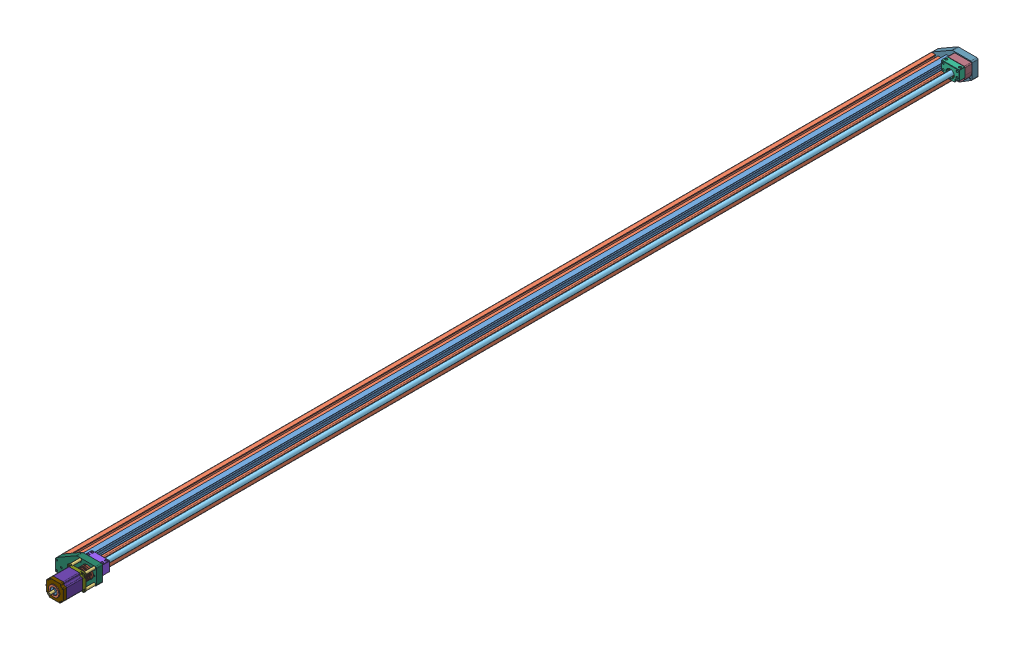
SolidWorks assembly Y Assembly, configuration Default. Lengths in mm.
Overall size (158.33 106.76 3065.8).
33 component instances, 22 part files, 30 mates.
Components (placement in the parent):
- Y 2897 track-1: Y 2897 track [Default] at (-10.0871 17.7743 0) x (-1 0 0) z (0 0 -1) size (23.2 18 2897)
- Y 2897 40x80 Aluminiun Extrusion-1: Y 2897 40x80 Aluminiun Extrusion [Default] at (-31.0945 -20 -2897) x (0 -1 0) z (0 0 -1) size (40 80 2897)
- Y Motor Spacer-1: Y Motor Spacer [Default] at (0 0 20) size (8.2 8.2 33.3)
- Y Screw-3: Y Screw [Default] at (30.9419 11.3979 -2874) x (-0.661218 -0.750194 0) z (0.750194 -0.661218 0) size (71.93 2929.31 73.44)
  - circlip for shafts normal_din2-1: circlip for shafts normal_din2 [Circlip DIN 471 - 10 x 1] at (-3.7337 -2.85 3.3256) x (-0.006153 0 0.999981) z (0 -1 0) size (12.16 14.7 1)
  - Y 2900 Ball Screw SFU1605-1: Y 2900 Ball Screw SFU1605 [По умолчанию] at (-2.5053 -2813.0019 -2.488) x (0 -1 0) z (-0.978395 0 -0.206744) size (2900 19.01 16.42)
  - BF12 BALLSCREW END SUPPORT-1: BF12 BALLSCREW END SUPPORT [Default] at (1.6957 -8.2224 -8.9513) x (0.661218 0 -0.750194) z (0 -1 0) size (60 43 20)
    - BF12-1-1: BF12-1 [Default] at (-12.8001 22.0446 -8.2224) size (60 43 20)
    - 6000-Bearing-1: 6000-Bearing [Default] at (-12.8001 4.0446 -2.2224) size (26 26 8)
  - BK12 BALLSCREW END SUPPORT-1: BK12 BALLSCREW END SUPPORT [Default] at (-17.1749 -2862.0215 6.1787) x (-0.661218 0 0.750194) z (0 1 0) size (60 43 25)
    - BK12-1-1: BK12-1 [Default] at (-11.028 26.197 -11.9785) size (60 43 25)
    - BK12-2-5: BK12-2 [Default] at (-11.028 8.197 8.0215) size (24 24 3)
    - 6001-Bearing-3: 6001-Bearing [Default] at (-11.028 8.197 0.0215) size (28 28 8)
    - 6001-Bearing-4: 6001-Bearing [Default] at (-11.028 8.197 -7.9785) size (28 28 8)
    - BK12-2-6: BK12-2 [Default] at (-11.028 8.197 -7.9785) x (-1 0 0) z (0 0 -1) size (24 24 3)
  - Flexible Coupling MKS-C-2-C-150-08-10-1: Flexible Coupling MKS-C-2-C-150-08-10 [Default] at (0.9582 -2912.8649 12.5563) x (-0.304543 0 0.952499) z (0.952499 0 0.304543) size (38.1 41.32 38.1)
    - MKS-C-2-C-150-08-10-1-1: MKS-C-2-C-150-08-10-1 [Default] at (-7.3634 16.4351 -7.2802) size (38.1 41.32 38.1)
    - socket head cap screw_am2-3: socket head cap screw_am2 [B18.3.1M - 4 x 0.7 x 20 Hex SHCS -- 20NHX] at (3.6866 10.4351 -20.2802) x (-1 0 0) z (0 0.924225 0.381849) size (24 7 7)
    - socket head cap screw_am2-4: socket head cap screw_am2 [B18.3.1M - 4 x 0.7 x 20 Hex SHCS -- 20NHX] at (-20.3634 -18.8649 -18.3302) x (0 0 1) z (-1 0 0) size (24 7 7)
- Y Screw end Support Spacer-1: Y Screw end Support Spacer [Default] at (44.8111 84 -2897) x (-1 0 0) z (0 0 1) size (60 55 23)
- Y Screw Support motor top end-1: Y Screw Support motor top end [Default] at (-541.0945 -130 -2917) x (0 -1 0) z (0 0 1) size (80.2 137 20)
- Y Screw Support motor top-1: Y Screw Support motor top [Default] at (-541.0945 -130 0) x (0 -1 0) z (0 0 1) size (80.2 137 20)
- Nema 23 Stepper Motor 57BYGH311D-12-1: Nema 23 Stepper Motor 57BYGH311D-12 [Default] at (24.3309 -0.4138 61.9741) x (-1 0 0) z (0 0 -1) size (58.4 56.4 121)
  - 57BYGH311D-12-1-1: 57BYGH311D-12-1 [Default] at (-11.5747 12.4138 -2.3259) size (56.4 56.4 14.6)
  - 57BYGH311D-12-2-1: 57BYGH311D-12-2 [Default] at (-11.5747 12.4138 -55.5259) size (56.4 56.4 53.2)
  - 57BYGH311D-12-3-1: 57BYGH311D-12-3 [Default] at (-11.5747 12.4138 -55.5259) x (-1 0 0) z (0 0 -1) size (56.4 56.4 11)
  - 57BYGH311D-12-4-2: 57BYGH311D-12-4 [Default] at (-11.5747 12.4138 -70.0259) size (36 36 15.4)
  - 57BYGH311D-12-5-1: 57BYGH311D-12-5 [Default] at (-11.5747 12.4138 -70.5259) x (0.622515 0.782608 0) z (0 0 1) size (35.3 35.21 5)
  - 57BYGH311D-12-6-1: 57BYGH311D-12-6 [Default] at (-11.5747 12.4138 -86.8259) size (8 8 121)
  - 57BYGH311D-12-7-1: 57BYGH311D-12-7 [Default] at (15.4253 12.4138 -61.0259) x (1 0 0) z (0 1 0) size (6.2 10.5 12)
- Y Motor Spacer-2: Y Motor Spacer [Default] at (6.3921 -56.1201 20) x (0.987351 0.158553 0) z (0 0 1) size (8.2 8.2 33.3)
- Y Motor Spacer-4: Y Motor Spacer [Default] at (-34.6432 -62.5167 20) x (0.959125 0.282984 0) z (0 0 1) size (8.2 8.2 33.3)
- Y Motor Spacer-6: Y Motor Spacer [Default] at (-15.1922 99.1687 20) x (-0.130134 -0.991496 0) z (0 0 1) size (8.2 8.2 33.3)
Mates (geometry in assembly coordinates):
- Concentric159: concentric aligned: cylinder of Y 2897 40x80 Aluminiun Extrusion-1 through (-26.0945 -5 -2904.0711) axis (0 0 1) radius 2.5; cylinder of ? through (-26.0945 -5 20) axis (0 0 1) radius 2.75
- Concentric160: concentric aligned: cylinder of Y 2897 40x80 Aluminiun Extrusion-1 through (-26.0945 -35 -2904.0711) axis (0 0 1) radius 2.5; cylinder of ? through (-26.0945 -35 20) axis (0 0 1) radius 2.75
- Coincident364: coincident anti-aligned: plane of Y 2897 40x80 Aluminiun Extrusion-1 through (45.9055 -3 0) normal (0 0 1); plane of ? through (-28.0945 -37 0) normal (0 0 -1)
- Concentric170: concentric aligned: cylinder of Y 2897 40x80 Aluminiun Extrusion-1 through (-66.0945 -5 -2904.0711) axis (0 0 1) radius 2.5; cylinder of Y Screw Support motor top end-1 through (-66.0945 -5 -2897) axis (0 0 1) radius 2.75
- Concentric171: concentric aligned: cylinder of Y 2897 40x80 Aluminiun Extrusion-1 through (-66.0945 -35 -2904.0711) axis (0 0 1) radius 2.5; cylinder of Y Screw Support motor top end-1 through (-66.0945 -35 -2897) axis (0 0 1) radius 2.75
- Concentric172: concentric aligned: cylinder of Y Screw-3/BF12 BALLSCREW END SUPPORT-1/BF12-1-1 through (58.9055 12 -2854) axis (0 0 -1) radius 2.75; cylinder of Y Screw end Support Spacer-1 through (58.9055 12 -2874) axis (0 0 -1) radius 2.7
- Coincident381: coincident: plane of Y 2897 40x80 Aluminiun Extrusion-1 through (24.8055 -40 -2986.4427) normal (0 -1 0); plane of Y 2897 track-1 through (399988.9055 0 -2897) normal (0 -1 0)
- Coincident382: coincident aligned: plane of Y 2897 40x80 Aluminiun Extrusion-1 through (378.9055 40 -2897) normal (0 0 -1); plane of Y 2897 track-1 through (0.5043 9.2384 -2897) normal (0 0 -1)
- Width2: width anti-aligned: plane of Y 2897 track-1 through (0.5043 -291536 -2897) normal (1 0 0); plane of Y 2897 track-1 through (-22.6932 -291536 -2897) normal (-1 0 0); plane of Y 2897 40x80 Aluminiun Extrusion-1 through (-6.9945 -3 -2986.4427) normal (-1 0 0); plane of Y 2897 40x80 Aluminiun Extrusion-1 through (-15.1945 0 -2986.4427) normal (1 0 0)
- Coincident383: coincident anti-aligned: plane of Y 2897 40x80 Aluminiun Extrusion-1 through (-46.9945 0 -2986.4427) normal (0 1 0); plane of Y 2897 track-1 through (399988.9055 0 -2897) normal (0 -1 0)
- Coincident384: coincident anti-aligned: plane of Y 2897 40x80 Aluminiun Extrusion-1 through (378.9055 40 -2897) normal (0 0 -1); plane of Y Screw Support motor top end-1 through (-68.0945 -37 -2897) normal (0 0 1)
- Concentric173: concentric aligned: cylinder of Y Screw end Support Spacer-1 through (58.9055 30 -2874) axis (0 0 -1) radius 2.7; cylinder of Y Screw Support motor top end-1 through (58.9055 30 -2917) axis (0 0 -1) radius 2.1
- Concentric174: concentric aligned: cylinder of Y Screw end Support Spacer-1 through (58.9055 12 -2874) axis (0 0 -1) radius 2.7; cylinder of Y Screw Support motor top end-1 through (58.9055 12 -2917) axis (0 0 -1) radius 2.1
- Concentric150: concentric aligned: cylinder of Y 2897 40x80 Aluminiun Extrusion-1 through (-66.0945 -35 -2904.0711) axis (0 0 1) radius 2.5; cylinder of Y Screw Support motor top-1 through (-66.0945 -35 20) axis (0 0 1) radius 2.75
- Concentric151: concentric aligned: cylinder of Y 2897 40x80 Aluminiun Extrusion-1 through (-66.0945 -5 -2904.0711) axis (0 0 1) radius 2.5; cylinder of Y Screw Support motor top-1 through (-66.0945 -5 20) axis (0 0 1) radius 2.75
- Coincident385: coincident anti-aligned: plane of Y 2897 40x80 Aluminiun Extrusion-1 through (5.9055 -3 0) normal (0 0 1); plane of Y Screw Support motor top-1 through (-68.0945 -37 0) normal (0 0 -1)
- Coincident386: coincident anti-aligned: plane of Y Screw-3/BF12 BALLSCREW END SUPPORT-1/BF12-1-1 through (5.9055 37 -2874) normal (0 0 -1); plane of Y Screw end Support Spacer-1 through (5.9055 37 -2874) normal (0 0 1)
- Coincident388: coincident anti-aligned: plane of Y Screw end Support Spacer-1 through (35.9055 12 -2897) normal (0 0 -1); plane of Y Screw Support motor top end-1 through (-68.0945 -37 -2897) normal (0 0 1)
- Concentric175: concentric anti-aligned: cylinder of Y Screw-3/BF12 BALLSCREW END SUPPORT-1/BF12-1-1 through (12.9055 30 -2854) axis (0 0 -1) radius 2.75; cylinder of Y Screw end Support Spacer-1 through (12.9055 30 -2874) axis (0 0 1) radius 2.7
- Distance2: distance = 2 mm anti-aligned: plane of Nema 23 Stepper Motor 57BYGH311D-12-1/57BYGH311D-12-1-1 through (10.7055 37.2 53.3) normal (0 0 -1); plane of Y Screw-3/Flexible Coupling MKS-C-2-C-150-08-10-1/MKS-C-2-C-150-08-10-1-1 through (18.4571 19.6456 55.3) normal (0 0 1)
- Concentric176: concentric anti-aligned: cylinder of Y Screw-3/Flexible Coupling MKS-C-2-C-150-08-10-1/MKS-C-2-C-150-08-10-1-1 through (35.9055 12 55.3) axis (0 0 1) radius 19.05; cylinder of Nema 23 Stepper Motor 57BYGH311D-12-1/57BYGH311D-12-6-1 through (35.9055 12 29.8) axis (0 0 -1) radius 4
- Concentric177: concentric aligned: cylinder of Y Screw Support motor top-1 through (59.4755 -11.57 20) axis (0 0 1) radius 2.1; cylinder of Nema 23 Stepper Motor 57BYGH311D-12-1/57BYGH311D-12-1-1 through (59.4755 -11.57 53.3) axis (0 0 1) radius 2.55
- Concentric178: concentric anti-aligned: cylinder of Y Motor Spacer-1 through (59.4755 35.57 64.8966) axis (0 0 -1) radius 4.1; cylinder of Nema 23 Stepper Motor 57BYGH311D-12-1/57BYGH311D-12-1-1 through (59.4755 35.57 53.3) axis (0 0 1) radius 2.55
- Coincident390: coincident anti-aligned: plane of Y Motor Spacer-1 through (59.4755 35.57 20) normal (0 0 -1); plane of Y Screw Support motor top-1 through (-68.0945 -37 20) normal (0 0 1)
- Concentric179: concentric anti-aligned: cylinder of Y Screw Support motor top-1 through (59.4755 -11.57 20) axis (0 0 1) radius 2.1; cylinder of Y Motor Spacer-2 through (59.4755 -11.57 64.8966) axis (0 0 -1) radius 4.1
- Coincident391: coincident anti-aligned: plane of Y Screw Support motor top-1 through (-68.0945 -37 20) normal (0 0 1); plane of Y Motor Spacer-2 through (59.4755 -11.57 20) normal (0 0 -1)
- Concentric180: concentric anti-aligned: cylinder of Y Screw Support motor top-1 through (12.3355 -11.57 20) axis (0 0 1) radius 2.1; cylinder of Y Motor Spacer-4 through (12.3355 -11.57 64.8966) axis (0 0 -1) radius 4.1
- Coincident392: coincident anti-aligned: plane of Y Screw Support motor top-1 through (-68.0945 -37 20) normal (0 0 1); plane of Y Motor Spacer-4 through (12.3355 -11.57 20) normal (0 0 -1)
- Coincident393: coincident anti-aligned: plane of Y Screw Support motor top-1 through (-68.0945 -37 20) normal (0 0 1); plane of Y Motor Spacer-6 through (12.3355 35.57 20) normal (0 0 -1)
- Concentric182: concentric anti-aligned: cylinder of Y Screw Support motor top-1 through (12.3355 35.57 20) axis (0 0 1) radius 2.1; cylinder of Y Motor Spacer-6 through (12.3355 35.57 64.8966) axis (0 0 -1) radius 4.1
